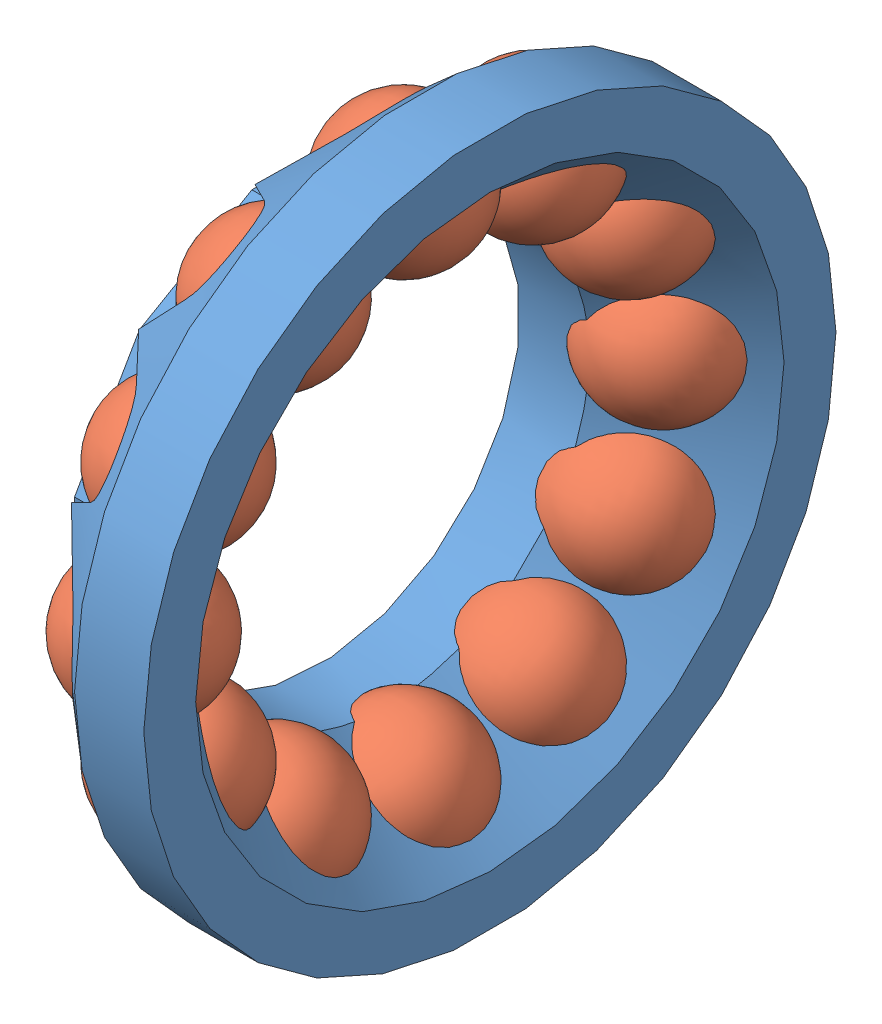
SolidWorks assembly подсборка подшипника, configuration По умолчанию. Lengths in mm.
Overall size (10 40 40).
13 component instances, 2 part files, 1 mates.
Components (placement in the parent):
- обойма подшипника 2-1: обойма подшипника 2 [По умолчанию] at origin size (10 40 40)
- шарик подшипника-1: шарик подшипника [По умолчанию] at (-3.4256 15 0) size (8 8 8)
- шарик подшипника-2: шарик подшипника [По умолчанию] at (-3.4256 12.9904 -7.5) x (1 0 0) z (0 0.5 0.866025) size (8 8 8)
- шарик подшипника-3: шарик подшипника [По умолчанию] at (-3.4256 7.5 -12.9904) x (1 0 0) z (0 0.866025 0.5) size (8 8 8)
- шарик подшипника-4: шарик подшипника [По умолчанию] at (-3.4256 0 -15) x (1 0 0) z (0 1 0) size (8 8 8)
- шарик подшипника-5: шарик подшипника [По умолчанию] at (-3.4256 -7.5 -12.9904) x (1 0 0) z (0 0.866025 -0.5) size (8 8 8)
- шарик подшипника-6: шарик подшипника [По умолчанию] at (-3.4256 -12.9904 -7.5) x (1 0 0) z (0 0.5 -0.866025) size (8 8 8)
- шарик подшипника-7: шарик подшипника [По умолчанию] at (-3.4256 -15 0) x (1 0 0) z (0 0 -1) size (8 8 8)
- шарик подшипника-8: шарик подшипника [По умолчанию] at (-3.4256 -12.9904 7.5) x (1 0 0) z (0 -0.5 -0.866025) size (8 8 8)
- шарик подшипника-9: шарик подшипника [По умолчанию] at (-3.4256 -7.5 12.9904) x (1 0 0) z (0 -0.866025 -0.5) size (8 8 8)
- шарик подшипника-10: шарик подшипника [По умолчанию] at (-3.4256 0 15) x (1 0 0) z (0 -1 0) size (8 8 8)
- шарик подшипника-11: шарик подшипника [По умолчанию] at (-3.4256 7.5 12.9904) x (1 0 0) z (0 -0.866025 0.5) size (8 8 8)
- шарик подшипника-12: шарик подшипника [По умолчанию] at (-3.4256 12.9904 7.5) x (1 0 0) z (0 -0.5 0.866025) size (8 8 8)
Mates (geometry in assembly coordinates):
- Концентричный1: concentric: sphere of обойма подшипника 2-1; sphere of шарик подшипника-1
